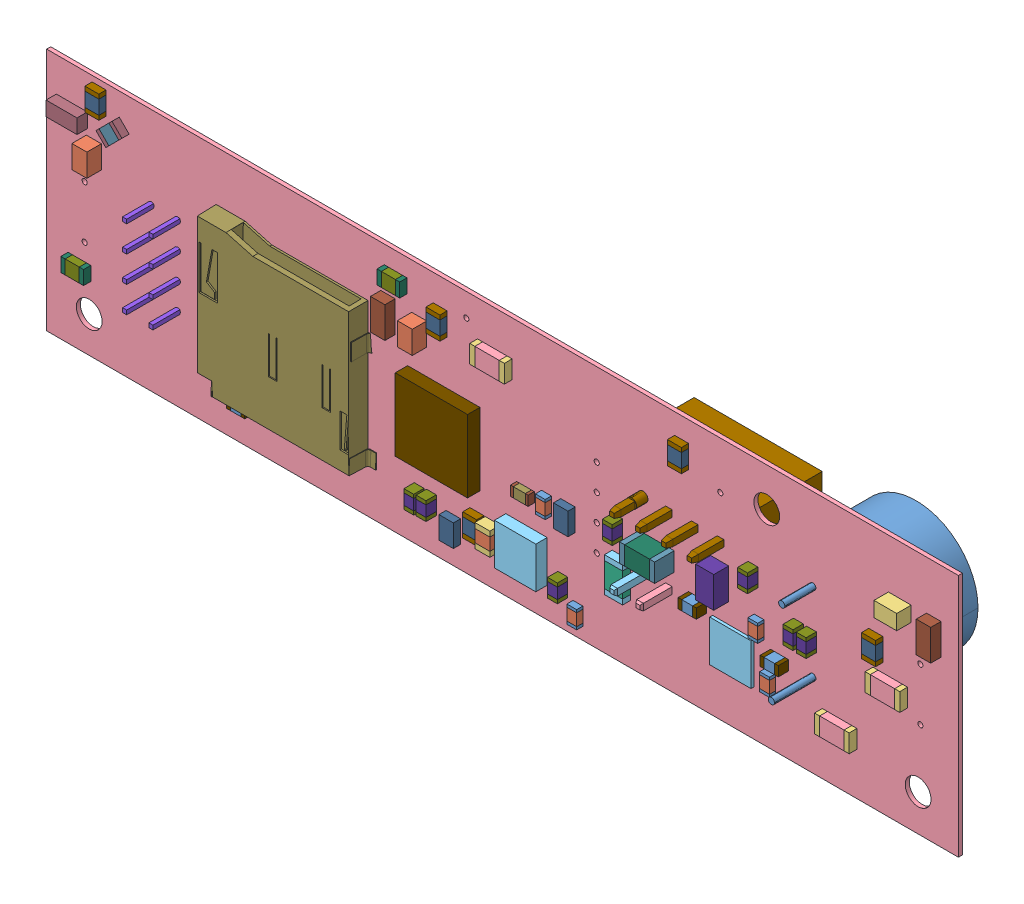
SolidWorks assembly PCB, configuration Default. Lengths in mm.
Overall size (88.26 23.62 14.15).
272 component instances, 42 part files, 0 mates.
Components (placement in the parent):
- R05-2-1: R05-2 [Default] at origin size (0.95 1.7 0.6)
  - 959206216-2-1: 959206216-2 [Default] at (123.9521 73.9609 0) size (0.95 0.27 0.6)
    - Extruded-62-1: Extruded-62 [Default] at origin size (0.95 0.27 0.6)
  - 959206352-2-1: 959206352-2 [Default] at (123.9521 74.6759 0) size (0.95 1.16 0.6)
    - Extruded-63-1: Extruded-63 [Default] at origin size (0.95 1.16 0.6)
  - 959206216-2-2: 959206216-2 [Default] at (123.9521 75.3909 0) size (0.95 0.27 0.6)
    - Extruded-62-1: Extruded-62 [Default] at origin size (0.95 0.27 0.6)
- R04-2-1: R04-2 [Default] at origin size (0.95 1.7 0.6)
  - 959206216-2-1: 959206216-2 [Default] at (141.478 81.581 0) size (0.95 0.27 0.6)
    - Extruded-62-1: Extruded-62 [Default] at origin size (0.95 0.27 0.6)
  - 959206352-2-1: 959206352-2 [Default] at (141.478 82.296 0) size (0.95 1.16 0.6)
    - Extruded-63-1: Extruded-63 [Default] at origin size (0.95 1.16 0.6)
  - 959206216-2-2: 959206216-2 [Default] at (141.478 83.011 0) size (0.95 0.27 0.6)
    - Extruded-62-1: Extruded-62 [Default] at origin size (0.95 0.27 0.6)
- R03-2-1: R03-2 [Default] at origin size (3.35 1.75 0.75)
  - 959206760-2-1: 959206760-2 [Default] at (147.8506 77.6516 0) size (0.49 1.75 0.75)
    - Extruded-64-1: Extruded-64 [Default] at origin size (0.49 1.75 0.75)
  - 959206896-2-1: 959206896-2 [Default] at (149.2781 77.6516 0) size (2.36 1.75 0.75)
    - Extruded-65-1: Extruded-65 [Default] at origin size (2.36 1.75 0.75)
  - 959206760-2-2: 959206760-2 [Default] at (150.7056 77.6516 0) size (0.49 1.75 0.75)
    - Extruded-64-1: Extruded-64 [Default] at origin size (0.49 1.75 0.75)
- R02-2-1: R02-2 [Default] at origin size (1.75 3.35 0.75)
  - 959207032-2-1: 959207032-2 [Default] at (128.1431 81.3844 0) size (1.75 0.49 0.75)
    - Extruded-66-1: Extruded-66 [Default] at origin size (1.75 0.49 0.75)
  - 959207168-2-1: 959207168-2 [Default] at (128.1431 79.9569 0) size (1.75 2.36 0.75)
    - Extruded-67-1: Extruded-67 [Default] at origin size (1.75 2.36 0.75)
  - 959207032-2-2: 959207032-2 [Default] at (128.1431 78.5294 0) size (1.75 0.49 0.75)
    - Extruded-66-1: Extruded-66 [Default] at origin size (1.75 0.49 0.75)
- R01-2-1: R01-2 [Default] at origin size (3.35 1.75 0.75)
  - 959206760-2-1: 959206760-2 [Default] at (117.3285 91.9479 0) size (0.49 1.75 0.75)
    - Extruded-64-1: Extruded-64 [Default] at origin size (0.49 1.75 0.75)
  - 959206896-2-1: 959206896-2 [Default] at (115.901 91.9479 0) size (2.36 1.75 0.75)
    - Extruded-65-1: Extruded-65 [Default] at origin size (2.36 1.75 0.75)
  - 959206760-2-2: 959206760-2 [Default] at (114.4735 91.9479 0) size (0.49 1.75 0.75)
    - Extruded-64-1: Extruded-64 [Default] at origin size (0.49 1.75 0.75)
- U3-2-1: U3-2 [Default] at origin size (43.25 15.95 5.5)
  - 959206080-2-1: 959206080-2 [Default] at (102.177 84.441 -2.3912) size (43.25 15.95 2)
    - Extruded-68-1: Extruded-68 [Default] at origin size (43.25 15.95 2)
  - 959205944-2-1: 959205944-2 [Default] at (85.217 88.291 -2.8912) size (0.4 0.4 5.5)
    - Extruded-69-1: Extruded-69 [Default] at origin size (0.4 0.4 5.5)
  - 959205944-2-2: 959205944-2 [Default] at (85.217 85.751 -2.8912) size (0.4 0.4 5.5)
    - Extruded-69-1: Extruded-69 [Default] at origin size (0.4 0.4 5.5)
  - 959205944-2-3: 959205944-2 [Default] at (82.677 88.291 -2.8912) size (0.4 0.4 5.5)
    - Extruded-69-1: Extruded-69 [Default] at origin size (0.4 0.4 5.5)
  - 959205944-2-4: 959205944-2 [Default] at (82.677 85.751 -2.8912) size (0.4 0.4 5.5)
    - Extruded-69-1: Extruded-69 [Default] at origin size (0.4 0.4 5.5)
  - 959205944-2-5: 959205944-2 [Default] at (85.217 83.211 -2.8912) size (0.4 0.4 5.5)
    - Extruded-69-1: Extruded-69 [Default] at origin size (0.4 0.4 5.5)
  - 959205944-2-6: 959205944-2 [Default] at (85.217 80.671 -2.8912) size (0.4 0.4 5.5)
    - Extruded-69-1: Extruded-69 [Default] at origin size (0.4 0.4 5.5)
  - 959205944-2-7: 959205944-2 [Default] at (82.677 83.211 -2.8912) size (0.4 0.4 5.5)
    - Extruded-69-1: Extruded-69 [Default] at origin size (0.4 0.4 5.5)
  - 959205944-2-8: 959205944-2 [Default] at (82.677 80.671 -2.8912) size (0.4 0.4 5.5)
    - Extruded-69-1: Extruded-69 [Default] at origin size (0.4 0.4 5.5)
- R11-2-1: R11-2 [Default] at origin size (1.35 2.2 0.7)
  - 959207304-2-1: 959207304-2 [Default] at (133.9849 94.0691 0) size (1.35 0.42 0.7)
    - Extruded-70-1: Extruded-70 [Default] at origin size (1.35 0.42 0.7)
  - 959207440-2-1: 959207440-2 [Default] at (133.9849 93.1791 0) size (1.35 1.36 0.7)
    - Extruded-71-1: Extruded-71 [Default] at origin size (1.35 1.36 0.7)
  - 959207304-2-2: 959207304-2 [Default] at (133.9849 92.2891 0) size (1.35 0.42 0.7)
    - Extruded-70-1: Extruded-70 [Default] at origin size (1.35 0.42 0.7)
- Q3-2-1: Q3-2 [Default] at origin size (1.4 3 1)
  - 959206624-2-1: 959206624-2 [Default] at (105.664 90.805 0.1) size (1.4 3 1)
    - Extruded-72-1: Extruded-72 [Default] at origin size (1.4 3 1)
- P6-2-1: P6-2 [Default] at origin size (16.31 15.21 2.47)
  - User Library-Micro SD-2-1: User Library-Micro SD-2 [Default] at (103.6713 76.9862 0.04) x (-1 0 0) z (0 0 1) size (16.31 15.21 2.47)
- Q1-2-1: Q1-2 [Default] at origin size (3 1.4 1)
  - 959206488-2-1: 959206488-2 [Default] at (75.057 92.3634 0.1) size (3 1.4 1)
    - Extruded-73-1: Extruded-73 [Default] at origin size (3 1.4 1)
- C1-2-1: C1-2 [Default] at origin size (3.4 1.8 1.9)
  - 959208392-2-1: 959208392-2 [Default] at (133.022 83.687 0) size (0.5 1.8 1.9)
    - Extruded-74-1: Extruded-74 [Default] at origin size (0.5 1.8 1.9)
  - 959208392-2-2: 959208392-2 [Default] at (130.122 83.687 0) size (0.5 1.8 1.9)
    - Extruded-74-1: Extruded-74 [Default] at origin size (0.5 1.8 1.9)
  - 959208256-2-1: 959208256-2 [Default] at (131.572 83.687 0) size (2.4 1.8 1.9)
    - Extruded-75-1: Extruded-75 [Default] at origin size (2.4 1.8 1.9)
- C2-2-1: C2-2 [Default] at origin size (0.95 1.75 1)
  - 959208664-2-1: 959208664-2 [Default] at (140.8925 85.698 0) size (0.95 0.35 1)
    - Extruded-76-1: Extruded-76 [Default] at origin size (0.95 0.35 1)
  - 959208664-2-2: 959208664-2 [Default] at (140.8925 87.098 0) size (0.95 0.35 1)
    - Extruded-76-1: Extruded-76 [Default] at origin size (0.95 0.35 1)
  - 959208528-2-1: 959208528-2 [Default] at (140.8925 86.398 0) size (0.95 1.05 1)
    - Extruded-77-1: Extruded-77 [Default] at origin size (0.95 1.05 1)
- C3-2-1: C3-2 [Default] at origin size (0.95 1.75 1)
  - 959208664-2-1: 959208664-2 [Default] at (146.558 83.0961 0) size (0.95 0.35 1)
    - Extruded-76-1: Extruded-76 [Default] at origin size (0.95 0.35 1)
  - 959208664-2-2: 959208664-2 [Default] at (146.558 84.4961 0) size (0.95 0.35 1)
    - Extruded-76-1: Extruded-76 [Default] at origin size (0.95 0.35 1)
  - 959208528-2-1: 959208528-2 [Default] at (146.558 83.7961 0) size (0.95 1.05 1)
    - Extruded-77-1: Extruded-77 [Default] at origin size (0.95 1.05 1)
- C5-2-1: C5-2 [Default] at origin size (1.75 0.95 1)
  - 959208936-2-1: 959208936-2 [Default] at (142.772 80.518 0) size (0.35 0.95 1)
    - Extruded-78-1: Extruded-78 [Default] at origin size (0.35 0.95 1)
  - 959208936-2-2: 959208936-2 [Default] at (144.172 80.518 0) size (0.35 0.95 1)
    - Extruded-78-1: Extruded-78 [Default] at origin size (0.35 0.95 1)
  - 959208800-2-1: 959208800-2 [Default] at (143.472 80.518 0) size (1.05 0.95 1)
    - Extruded-79-1: Extruded-79 [Default] at origin size (1.05 0.95 1)
- C6-2-1: C6-2 [Default] at origin size (1.75 0.95 1)
  - 959208800-2-1: 959208800-2 [Default] at (135.5285 81.379 0) size (1.05 0.95 1)
    - Extruded-79-1: Extruded-79 [Default] at origin size (1.05 0.95 1)
  - 959208936-2-1: 959208936-2 [Default] at (136.2285 81.379 0) size (0.35 0.95 1)
    - Extruded-78-1: Extruded-78 [Default] at origin size (0.35 0.95 1)
  - 959208936-2-2: 959208936-2 [Default] at (134.8286 81.379 0) size (0.35 0.95 1)
    - Extruded-78-1: Extruded-78 [Default] at origin size (0.35 0.95 1)
- C7-2-1: C7-2 [Default] at origin size (0.95 1.75 1)
  - 959208528-2-1: 959208528-2 [Default] at (145.288 83.8282 0) size (0.95 1.05 1)
    - Extruded-77-1: Extruded-77 [Default] at origin size (0.95 1.05 1)
  - 959208664-2-1: 959208664-2 [Default] at (145.288 83.1282 0) size (0.95 0.35 1)
    - Extruded-76-1: Extruded-76 [Default] at origin size (0.95 0.35 1)
  - 959208664-2-2: 959208664-2 [Default] at (145.288 84.5282 0) size (0.95 0.35 1)
    - Extruded-76-1: Extruded-76 [Default] at origin size (0.95 0.35 1)
- C8-2-1: C8-2 [Default] at origin size (1.45 2.2 1)
  - 959207984-2-1: 959207984-2 [Default] at (115.697 77.2073 0) size (1.45 1.2 1)
    - Extruded-80-1: Extruded-80 [Default] at origin size (1.45 1.2 1)
  - 959207848-2-1: 959207848-2 [Default] at (115.697 78.0573 0) size (1.45 0.5 1)
    - Extruded-81-1: Extruded-81 [Default] at origin size (1.45 0.5 1)
  - 959207848-2-2: 959207848-2 [Default] at (115.697 76.3573 0) size (1.45 0.5 1)
    - Extruded-81-1: Extruded-81 [Default] at origin size (1.45 0.5 1)
- C9-2-1: C9-2 [Default] at origin size (0.95 1.75 1)
  - 959208528-2-1: 959208528-2 [Default] at (108.577 76.835 0) size (0.95 1.05 1)
    - Extruded-77-1: Extruded-77 [Default] at origin size (0.95 1.05 1)
  - 959208664-2-1: 959208664-2 [Default] at (108.577 76.135 0) size (0.95 0.35 1)
    - Extruded-76-1: Extruded-76 [Default] at origin size (0.95 0.35 1)
  - 959208664-2-2: 959208664-2 [Default] at (108.577 77.535 0) size (0.95 0.35 1)
    - Extruded-76-1: Extruded-76 [Default] at origin size (0.95 0.35 1)
- C10-2-1: C10-2 [Default] at origin size (0.95 1.75 1)
  - 959208664-2-1: 959208664-2 [Default] at (109.7632 77.5843 0) size (0.95 0.35 1)
    - Extruded-76-1: Extruded-76 [Default] at origin size (0.95 0.35 1)
  - 959208664-2-2: 959208664-2 [Default] at (109.7632 76.1843 0) size (0.95 0.35 1)
    - Extruded-76-1: Extruded-76 [Default] at origin size (0.95 0.35 1)
  - 959208528-2-1: 959208528-2 [Default] at (109.7632 76.8843 0) size (0.95 1.05 1)
    - Extruded-77-1: Extruded-77 [Default] at origin size (0.95 1.05 1)
- C11-2-1: C11-2 [Default] at origin size (0.95 1.75 1)
  - 959208664-2-1: 959208664-2 [Default] at (122.4827 75.652 0) size (0.95 0.35 1)
    - Extruded-76-1: Extruded-76 [Default] at origin size (0.95 0.35 1)
  - 959208664-2-2: 959208664-2 [Default] at (122.4827 77.052 0) size (0.95 0.35 1)
    - Extruded-76-1: Extruded-76 [Default] at origin size (0.95 0.35 1)
  - 959208528-2-1: 959208528-2 [Default] at (122.4827 76.352 0) size (0.95 1.05 1)
    - Extruded-77-1: Extruded-77 [Default] at origin size (0.95 1.05 1)
- C12-2-1: C12-2 [Default] at origin size (1.75 0.95 1)
  - 959208936-2-1: 959208936-2 [Default] at (92.521 76.327 0) size (0.35 0.95 1)
    - Extruded-78-1: Extruded-78 [Default] at origin size (0.35 0.95 1)
  - 959208936-2-2: 959208936-2 [Default] at (91.121 76.327 0) size (0.35 0.95 1)
    - Extruded-78-1: Extruded-78 [Default] at origin size (0.35 0.95 1)
  - 959208800-2-1: 959208800-2 [Default] at (91.821 76.327 0) size (1.05 0.95 1)
    - Extruded-79-1: Extruded-79 [Default] at origin size (1.05 0.95 1)
- P1-2-1: P1-2 [Default] at origin size (7.4 5.75 10.4)
  - P1-subassembly-1-2-1: P1-subassembly-1-2 [Default] at (131.5051 81.6569 -0.3912) x (-1 0 0) z (0 -1 0) size (7.4 10.4 5.75)
    - User Library-JST B2B-XH-A-10-1: User Library-JST B2B-XH-A-10 [Default] at origin size (0.64 3.4 0.64)
    - User Library-JST B2B-XH-A-11-1: User Library-JST B2B-XH-A-11 [Default] at origin size (0.64 3.4 0.64)
    - User Library-JST B2B-XH-A-12-1: User Library-JST B2B-XH-A-12 [Default] at origin size (0.64 4.5 0.64)
    - User Library-JST B2B-XH-A-13-1: User Library-JST B2B-XH-A-13 [Default] at origin size (0.64 4.5 0.64)
    - User Library-JST B2B-XH-A-14-1: User Library-JST B2B-XH-A-14 [Default] at origin size (7.4 7 5.75)
- P3-2-1: P3-2 [Default] at origin size (12.4 5.75 10.4)
  - SW3dPS-jst-b4b-xh-a-1-2-1: SW3dPS-jst-b4b-xh-a-1-2 [Default] at (134.0049 88.1301 -0.3912) x (-1 0 0) z (0 -1 0) size (12.4 10.4 5.75)
- P4-2-1: P4-2 [Default] at origin
  - connector-2-1: connector-2 [Default] at (76.2639 56.9549 -0.3912) x (0 1 0) z (0 0 -1)
- P5-2-1: P5-2 [Default] at origin
  - connector-2-1: connector-2 [Default] at (157.0351 111.9551 -0.3912) x (0 -1 0) z (0 0 -1)
- Q2-2-1: Q2-2 [Default] at origin size (1.4 3 1)
  - 959206624-2-1: 959206624-2 [Default] at (158.496 90.17 0.1) size (1.4 3 1)
    - Extruded-72-1: Extruded-72 [Default] at origin size (1.4 3 1)
- R1-2-1: R1-2 [Default] at origin size (0.95 1.7 0.6)
  - 959206216-2-1: 959206216-2 [Default] at (142.6211 77.6287 0) size (0.95 0.27 0.6)
    - Extruded-62-1: Extruded-62 [Default] at origin size (0.95 0.27 0.6)
  - 959206352-2-1: 959206352-2 [Default] at (142.6211 78.3437 0) size (0.95 1.16 0.6)
    - Extruded-63-1: Extruded-63 [Default] at origin size (0.95 1.16 0.6)
  - 959206216-2-2: 959206216-2 [Default] at (142.6211 79.0587 0) size (0.95 0.27 0.6)
    - Extruded-62-1: Extruded-62 [Default] at origin size (0.95 0.27 0.6)
- R2-2-1: R2-2 [Default] at origin size (1.4 2.15 0.7)
  - 959208120-2-1: 959208120-2 [Default] at (111.8912 75.852 0) size (1.4 2.15 0.7)
    - Extruded-82-1: Extruded-82 [Default] at origin size (1.4 2.15 0.7)
- R3-2-1: R3-2 [Default] at origin size (1.35 2.2 0.7)
  - 959207304-2-1: 959207304-2 [Default] at (114.1729 78.1061 0) size (1.35 0.42 0.7)
    - Extruded-70-1: Extruded-70 [Default] at origin size (1.35 0.42 0.7)
  - 959207440-2-1: 959207440-2 [Default] at (114.1729 77.2161 0) size (1.35 1.36 0.7)
    - Extruded-71-1: Extruded-71 [Default] at origin size (1.35 1.36 0.7)
  - 959207304-2-2: 959207304-2 [Default] at (114.1729 76.3261 0) size (1.35 0.42 0.7)
    - Extruded-70-1: Extruded-70 [Default] at origin size (1.35 0.42 0.7)
- R4-2-1: R4-2 [Default] at origin size (1.7 0.95 0.6)
  - 959209072-2-1: 959209072-2 [Default] at (119.5871 82.2961 0) size (0.27 0.95 0.6)
    - Extruded-83-1: Extruded-83 [Default] at origin size (0.27 0.95 0.6)
  - 959209208-2-1: 959209208-2 [Default] at (118.8721 82.2961 0) size (1.16 0.95 0.6)
    - Extruded-84-1: Extruded-84 [Default] at origin size (1.16 0.95 0.6)
  - 959209072-2-2: 959209072-2 [Default] at (118.1571 82.2961 0) size (0.27 0.95 0.6)
    - Extruded-83-1: Extruded-83 [Default] at origin size (0.27 0.95 0.6)
- R5-2-1: R5-2 [Default] at origin size (0.95 1.7 0.6)
  - 959206216-2-1: 959206216-2 [Default] at (120.9041 81.6699 0) size (0.95 0.27 0.6)
    - Extruded-62-1: Extruded-62 [Default] at origin size (0.95 0.27 0.6)
  - 959206352-2-1: 959206352-2 [Default] at (120.9041 82.3849 0) size (0.95 1.16 0.6)
    - Extruded-63-1: Extruded-63 [Default] at origin size (0.95 1.16 0.6)
  - 959206216-2-2: 959206216-2 [Default] at (120.9041 83.0999 0) size (0.95 0.27 0.6)
    - Extruded-62-1: Extruded-62 [Default] at origin size (0.95 0.27 0.6)
- R6-2-1: R6-2 [Default] at origin size (1.4 2.15 0.7)
  - 959208120-2-1: 959208120-2 [Default] at (122.9827 82.385 0) size (1.4 2.15 0.7)
    - Extruded-82-1: Extruded-82 [Default] at origin size (1.4 2.15 0.7)
- R8-2-1: R8-2 [Default] at origin size (2.51 2.51 0.7)
  - 959207576-2-1: 959207576-2 [Default] at (78.6187 92.1936 0) size (1.25 1.25 0.7)
    - Extruded-85-1: Extruded-85 [Default] at origin size (1.25 1.25 0.7)
  - 959207712-2-1: 959207712-2 [Default] at (79.248 92.8229 0) size (1.92 1.92 0.7)
    - Extruded-86-1: Extruded-86 [Default] at origin size (1.92 1.92 0.7)
  - 959207576-2-2: 959207576-2 [Default] at (79.8773 93.4522 0) size (1.25 1.25 0.7)
    - Extruded-85-1: Extruded-85 [Default] at origin size (1.25 1.25 0.7)
- R13-2-1: R13-2 [Default] at origin size (2.2 1.35 0.7)
  - 959209344-2-1: 959209344-2 [Default] at (105.4089 93.8529 0) size (0.42 1.35 0.7)
    - Extruded-87-1: Extruded-87 [Default] at origin size (0.42 1.35 0.7)
  - 959209480-2-1: 959209480-2 [Default] at (106.2989 93.8529 0) size (1.36 1.35 0.7)
    - Extruded-88-1: Extruded-88 [Default] at origin size (1.36 1.35 0.7)
  - 959209344-2-2: 959209344-2 [Default] at (107.1889 93.8529 0) size (0.42 1.35 0.7)
    - Extruded-87-1: Extruded-87 [Default] at origin size (0.42 1.35 0.7)
- R7-2-1: R7-2 [Default] at origin size (2.2 1.35 0.7)
  - 959209344-2-1: 959209344-2 [Default] at (76.5821 79.5961 0) size (0.42 1.35 0.7)
    - Extruded-87-1: Extruded-87 [Default] at origin size (0.42 1.35 0.7)
  - 959209480-2-1: 959209480-2 [Default] at (75.6921 79.5961 0) size (1.36 1.35 0.7)
    - Extruded-88-1: Extruded-88 [Default] at origin size (1.36 1.35 0.7)
  - 959209344-2-2: 959209344-2 [Default] at (74.8021 79.5961 0) size (0.42 1.35 0.7)
    - Extruded-87-1: Extruded-87 [Default] at origin size (0.42 1.35 0.7)
- R9-2-1: R9-2 [Default] at origin size (1.35 2.2 0.7)
  - 959207304-2-1: 959207304-2 [Default] at (77.5971 95.5049 0) size (1.35 0.42 0.7)
    - Extruded-70-1: Extruded-70 [Default] at origin size (1.35 0.42 0.7)
  - 959207440-2-1: 959207440-2 [Default] at (77.5971 94.6149 0) size (1.35 1.36 0.7)
    - Extruded-71-1: Extruded-71 [Default] at origin size (1.35 1.36 0.7)
  - 959207304-2-2: 959207304-2 [Default] at (77.5971 93.7249 0) size (1.35 0.42 0.7)
    - Extruded-70-1: Extruded-70 [Default] at origin size (1.35 0.42 0.7)
- R14-2-1: R14-2 [Default] at origin size (1.35 2.2 0.7)
  - 959207304-2-1: 959207304-2 [Default] at (110.6132 93.495 0) size (1.35 0.42 0.7)
    - Extruded-70-1: Extruded-70 [Default] at origin size (1.35 0.42 0.7)
  - 959207440-2-1: 959207440-2 [Default] at (110.6132 92.605 0) size (1.35 1.36 0.7)
    - Extruded-71-1: Extruded-71 [Default] at origin size (1.35 1.36 0.7)
  - 959207304-2-2: 959207304-2 [Default] at (110.6132 91.715 0) size (1.35 0.42 0.7)
    - Extruded-70-1: Extruded-70 [Default] at origin size (1.35 0.42 0.7)
- R10-2-1: R10-2 [Default] at origin size (3.35 1.75 0.75)
  - 959206760-2-1: 959206760-2 [Default] at (152.7506 83.5661 0) size (0.49 1.75 0.75)
    - Extruded-64-1: Extruded-64 [Default] at origin size (0.49 1.75 0.75)
  - 959206896-2-1: 959206896-2 [Default] at (154.1781 83.5661 0) size (2.36 1.75 0.75)
    - Extruded-65-1: Extruded-65 [Default] at origin size (2.36 1.75 0.75)
  - 959206760-2-2: 959206760-2 [Default] at (155.6056 83.5661 0) size (0.49 1.75 0.75)
    - Extruded-64-1: Extruded-64 [Default] at origin size (0.49 1.75 0.75)
- R12-2-1: R12-2 [Default] at origin size (1.35 2.2 0.7)
  - 959207304-2-1: 959207304-2 [Default] at (152.7811 87.2879 0) size (1.35 0.42 0.7)
    - Extruded-70-1: Extruded-70 [Default] at origin size (1.35 0.42 0.7)
  - 959207440-2-1: 959207440-2 [Default] at (152.7811 86.3979 0) size (1.35 1.36 0.7)
    - Extruded-71-1: Extruded-71 [Default] at origin size (1.35 1.36 0.7)
  - 959207304-2-2: 959207304-2 [Default] at (152.7811 85.5079 0) size (1.35 0.42 0.7)
    - Extruded-70-1: Extruded-70 [Default] at origin size (1.35 0.42 0.7)
- U1-2-1: U1-2 [Default] at origin size (1.75 3 1.45)
  - 959209616-2-1: 959209616-2 [Default] at (137.668 84.449 0) size (1.75 3 1.45)
    - Extruded-89-1: Extruded-89 [Default] at origin size (1.75 3 1.45)
- U4-2-1: U4-2 [Default] at origin size (7 7 1.2)
  - 959209752-2-1: 959209752-2 [Default] at (110.9632 83.702 0) size (7 7 1.2)
    - Extruded-90-1: Extruded-90 [Default] at origin size (7 7 1.2)
- BUZ1-2-1: BUZ1-2 [Default] at origin size (12 15.45 14.15)
  - SW3dPS-WST-1203UX-2-1: SW3dPS-WST-1203UX-2 [Default] at (146.685 84.5049 -0.4912) x (0 -1 0) z (1 0 0) size (15.45 14.15 12)
- C4-2-1: C4-2 [Default] at origin size (0.95 1.75 1)
  - 959208528-2-1: 959208528-2 [Default] at (127.791 83.885 0) size (0.95 1.05 1)
    - Extruded-77-1: Extruded-77 [Default] at origin size (0.95 1.05 1)
  - 959208664-2-1: 959208664-2 [Default] at (127.791 83.185 0) size (0.95 0.35 1)
    - Extruded-76-1: Extruded-76 [Default] at origin size (0.95 0.35 1)
  - 959208664-2-2: 959208664-2 [Default] at (127.791 84.585 0) size (0.95 0.35 1)
    - Extruded-76-1: Extruded-76 [Default] at origin size (0.95 0.35 1)
- D1-2-1: D1-2 [Default] at origin size (1.45 2.2 1.4)
  - 959209888-2-1: 959209888-2 [Default] at (77.089 89.876 0) size (1.45 2.2 1.4)
    - Extruded-91-1: Extruded-91 [Default] at origin size (1.45 2.2 1.4)
- D2-2-1: D2-2 [Default] at origin size (2.2 1.45 1.4)
  - 959210024-2-1: 959210024-2 [Default] at (155.107 90.769 0) size (2.2 1.45 1.4)
    - Extruded-92-1: Extruded-92 [Default] at origin size (2.2 1.45 1.4)
- D3-2-1: D3-2 [Default] at origin size (1.45 2.2 1.4)
  - 959209888-2-1: 959209888-2 [Default] at (108.585 90.769 0) size (1.45 2.2 1.4)
    - Extruded-91-1: Extruded-91 [Default] at origin size (1.45 2.2 1.4)
- Board-2-1: Board-2 [Default] at origin size (88.26 23.62 0.39)
- BMP180-1: BMP180 [По умолчанию] at (136.9834 77.0265 -0.8167) size (4 4 1.1)
- BMP180-2: BMP180 [По умолчанию] at (117.2276 75.8002 0.2576) size (4 4 1.1)
